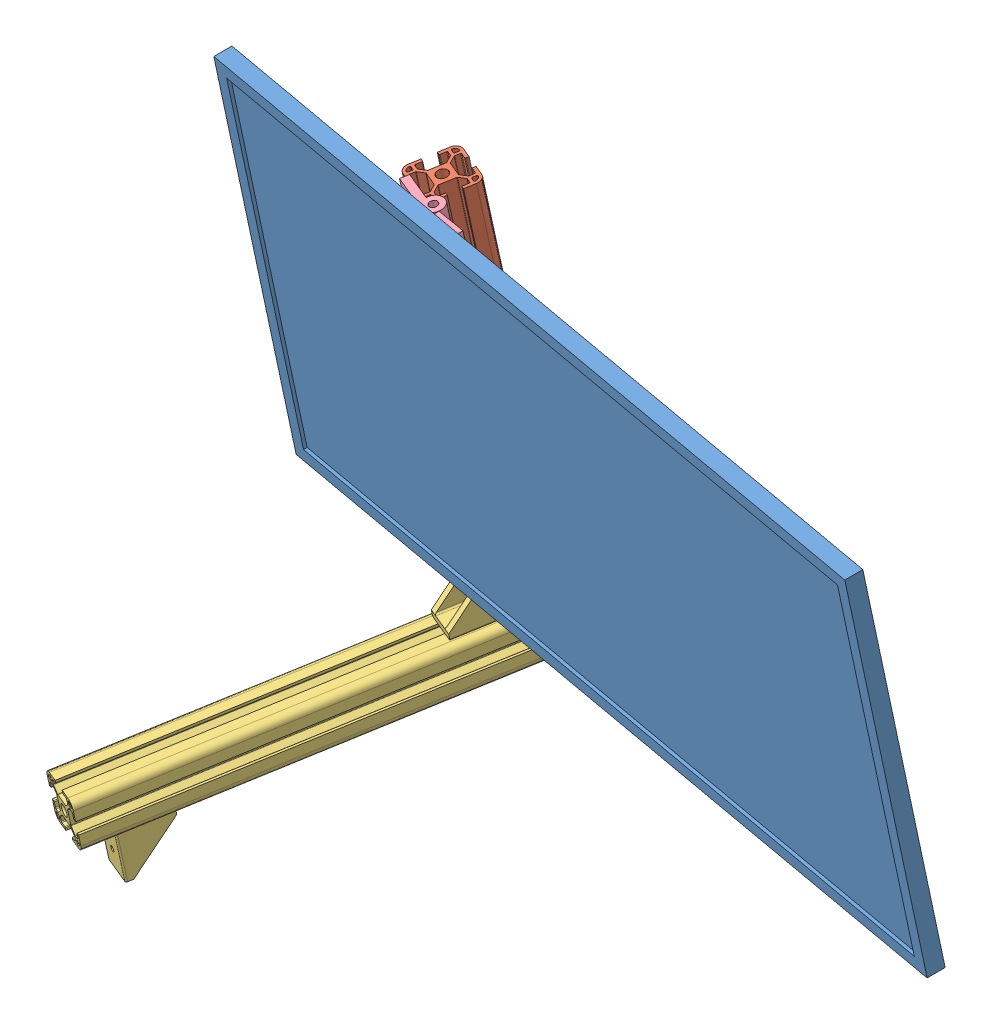
SolidWorks assembly 螢幕組, configuration 預設. Lengths in mm.
Overall size (544.01 439.81 254.23).
13 component instances, 4 part files, 25 mates.
Components (placement in the parent):
- 螢幕-1: 螢幕 [圓棒變滑塊] at (22.4284 66.6222 472.1885) x (0.983432 0.005828 0.181183) z (-0.177064 -0.183339 0.966972) size (500 240 30)
- 螢幕支架用鋁擠-2: 螢幕支架用鋁擠 [3030-250] at (88.7875 74.1628 449.5739) x (0.051386 -0.982878 -0.176946) z (0.982857 0.018358 0.183454) size (30 30 250)
- 鋁擠-2: 鋁擠 [溝槽] at (26.1822 70.509 451.6887) x (0.051386 -0.982878 -0.176946) z (0.982857 0.018358 0.183454) size (14.45 6.3 14)
- 鋁擠-3: 鋁擠 [3030-250] at (-252.8341 -209.0363 530.365) x (0.927532 -0.018707 0.373275) z (-0.370194 -0.183304 0.91069) size (30 30 250)
- 鋁擠-4: 鋁擠 [直角支架] at (-172.1622 -153.9662 332.6674) x (0.370194 0.183304 -0.91069) z (0.927532 -0.018707 0.373275) size (30 30 20)
- 鋁擠-5: 鋁擠 [溝槽] at (-178.3939 -158.2618 347.9368) x (-0.927532 0.018707 -0.373275) z (-0.370194 -0.183304 0.91069) size (14.45 6.3 14)
- 鉸鏈-1: 鉸鏈 [預設] at (-163.4821 123.0237 390.3048) x (0.982857 0.018358 0.183454) z (0.051386 -0.982878 -0.176946) size (50.7 17.96 50)
  - 鉸鏈-1: 鉸鏈 [左] at (0.4631 0.6018 25) size (31 12 50)
  - 鉸鏈-2: 鉸鏈 [右] at (0.4631 0.6018 25) x (0.979767 0.200143 0) z (0 0 1) size (31 12 50)
- 螢幕支架用鋁擠-1: 螢幕支架用鋁擠 [溝槽] at (-172.5916 -137.0373 334.5826) x (0.927532 -0.018707 0.373275) z (-0.051386 0.982878 0.176946) size (14.45 6.3 14)
- 螢幕支架用鋁擠-3: 螢幕支架用鋁擠 [3030-250] at (-166.6093 -151.2166 319.007) x (0.927532 -0.018707 0.373275) z (0.051386 -0.982878 -0.176946) size (30 30 250)
- 鋁擠-6: 鋁擠 [溝槽] at (-239.0663 -216.1339 495.7984) x (-0.927532 0.018707 -0.373275) z (0.370194 0.183304 -0.91069) size (14.45 6.3 14)
- 鋁擠-7: 鋁擠 [直角支架] at (-245.2979 -220.4296 511.0678) x (-0.370194 -0.183304 0.91069) z (0.927532 -0.018707 0.373275) size (30 30 20)
Mates (geometry in assembly coordinates):
- 重合/共線/共點1: coincident anti-aligned: plane of 螢幕支架用鋁擠-2 through (-159.4351 71.1214 416.9887) normal (0.177064 0.183339 -0.966972); plane of 鋁擠-2 through (33.0034 74.6174 452.8894) normal (-0.177064 -0.183339 0.966972)
- 同軸心1: concentric anti-aligned: cylinder of 螢幕-1 through (24.1991 68.4556 462.5188) axis (0.177064 0.183339 -0.966972) radius 1.65; cylinder of 鋁擠-2 through (26.1822 70.509 451.6887) axis (-0.177064 -0.183339 0.966972) radius 1.65
- 寬度1: width anti-aligned: plane of 鋁擠-2 through (33.3511 66.896 451.7993) normal (0.051386 -0.982878 -0.176946); plane of 鋁擠-2 through (32.9503 74.5624 453.1795) normal (-0.051386 0.982878 0.176946); plane of 螢幕支架用鋁擠-2 through (-159.3781 62.8917 417.5071) normal (-0.051386 0.982878 0.176946); plane of 螢幕支架用鋁擠-2 through (-159.7892 70.7547 418.9227) normal (0.051386 -0.982878 -0.176946)
- 重合/共線/共點2: coincident anti-aligned: plane of 螢幕-1 through (-2.3676 40.6232 442.0355) normal (0.177064 0.183339 -0.966972); plane of 螢幕支架用鋁擠-2 through (-160.1222 77.1434 420.073) normal (-0.177064 -0.183339 0.966972)
- 重合/共線/共點4: coincident anti-aligned: plane of 螢幕支架用鋁擠-2 through (-154.8103 82.6436 391.0638) normal (0.177064 0.183339 -0.966972); plane of 鉸鏈-1/鉸鏈-1 through (-190.0648 146.1799 396.6549) normal (-0.177064 -0.183339 0.966972)
- 同軸心2: concentric aligned: cylinder of 螢幕支架用鋁擠-2 through (-148.3032 81.3867 399.9354) axis (0.177064 0.183339 -0.966972) radius 2; cylinder of 鉸鏈-1/鉸鏈-1 through (-146.9476 82.7903 392.5324) axis (0.177064 0.183339 -0.966972) radius 2
- 同軸心3: concentric aligned: cylinder of 螢幕支架用鋁擠-2 through (-147.2755 61.7291 396.3965) axis (0.177064 0.183339 -0.966972) radius 2; cylinder of 鉸鏈-1/鉸鏈-1 through (-145.9199 63.1327 388.9935) axis (0.177064 0.183339 -0.966972) radius 2
- 同軸心5: concentric anti-aligned: cylinder of 鉸鏈-1/鉸鏈-2 through (-177.6375 82.7959 383.5888) axis (0.370194 0.183304 -0.91069) radius 2; cylinder of 螢幕支架用鋁擠-3 through (-172.9516 85.1161 372.0614) axis (-0.370194 -0.183304 0.91069) radius 2
- 同軸心6: concentric anti-aligned: cylinder of 鉸鏈-1/鉸鏈-2 through (-176.6097 63.1383 380.0498) axis (0.370194 0.183304 -0.91069) radius 2; cylinder of 螢幕支架用鋁擠-3 through (-171.9239 65.4586 368.5225) axis (-0.370194 -0.183304 0.91069) radius 2
- 重合/共線/共點6: coincident anti-aligned: plane of 鉸鏈-1/鉸鏈-2 through (-187.9895 148.0233 387.0182) normal (0.370194 0.183304 -0.91069); plane of 螢幕支架用鋁擠-3 through (-194.7479 91.9498 372.9845) normal (-0.370194 -0.183304 0.91069)
- 重合/共線/共點7: coincident anti-aligned: plane of 螢幕支架用鋁擠-1 through (-176.2725 -129.9376 333.6369) normal (-0.370194 -0.183304 0.91069); plane of 螢幕支架用鋁擠-3 through (-187.9786 92.1958 373.5896) normal (0.370194 0.183304 -0.91069)
- 寬度2: width aligned: plane of 螢幕支架用鋁擠-1 through (-176.3835 -129.9926 333.9102) normal (-0.927532 0.018707 -0.373275); plane of 螢幕支架用鋁擠-1 through (-169.1488 -130.1385 336.8217) normal (0.927532 -0.018707 0.373275); plane of 螢幕支架用鋁擠-3 through (-181.2987 91.6795 378.3971) normal (-0.927532 0.018707 -0.373275); plane of 螢幕支架用鋁擠-3 through (-188.719 91.8292 375.4109) normal (0.927532 -0.018707 0.373275)
- 同軸心7: concentric aligned: cylinder of 鋁擠-4 through (-174.5166 -137.9905 339.3182) axis (-0.370194 -0.183304 0.91069) radius 1.65; cylinder of 螢幕支架用鋁擠-1 through (-172.5916 -137.0373 334.5826) axis (-0.370194 -0.183304 0.91069) radius 1.65
- 重合/共線/共點8: coincident anti-aligned: plane of 鋁擠-4 through (-162.8869 -154.1533 336.4001) normal (0.370194 0.183304 -0.91069); plane of 螢幕支架用鋁擠-3 through (-194.7479 91.9498 372.9845) normal (-0.370194 -0.183304 0.91069)
- 重合/共線/共點9: coincident anti-aligned: plane of 鋁擠-3 through (-164.6634 -150.3578 303.4988) normal (0.051386 -0.982878 -0.176946); plane of 鋁擠-5 through (-177.3267 -160.4042 355.6258) normal (-0.051386 0.982878 0.176946)
- 寬度3: width anti-aligned: plane of 鋁擠-5 through (-184.5769 -159.9634 352.7674) normal (-0.927532 0.018707 -0.373275); plane of 鋁擠-5 through (-177.3421 -160.1094 355.6789) normal (0.927532 -0.018707 0.373275); plane of 鋁擠-3 through (-164.7662 -148.3921 303.8527) normal (0.927532 -0.018707 0.373275); plane of 鋁擠-3 through (-157.3459 -148.5417 306.8389) normal (-0.927532 0.018707 -0.373275)
- 同軸心8: concentric aligned: cylinder of 鋁擠-4 through (-178.6611 -153.1509 348.8569) axis (-0.051386 0.982878 0.176946) radius 1.65; cylinder of 鋁擠-5 through (-178.3939 -158.2618 347.9368) axis (-0.051386 0.982878 0.176946) radius 1.65
- 重合/共線/共點10: coincident anti-aligned: plane of 鋁擠-3 through (-170.7955 -148.2707 301.4273) normal (-0.051386 0.982878 0.176946); plane of 鋁擠-4 through (-162.8869 -154.1533 336.4001) normal (0.051386 -0.982878 -0.176946)
- 重合/共線/共點11: coincident anti-aligned: plane of 鋁擠-3 through (-170.7955 -148.2707 301.4273) normal (-0.051386 0.982878 0.176946); plane of 螢幕支架用鋁擠-3 through (-180.2354 -152.9449 324.6499) normal (0.051386 -0.982878 -0.176946)
- 重合/共線/共點12: coincident aligned: plane of 鋁擠-3 through (-170.5643 -152.6936 300.6311) normal (0.370194 0.183304 -0.91069); plane of 螢幕支架用鋁擠-3 through (-183.642 97.4489 345.6638) normal (0.370194 0.183304 -0.91069)
- 重合/共線/共點13: coincident anti-aligned: plane of 鋁擠-3 through (-155.9071 -176.0623 301.8844) normal (-0.051386 0.982878 0.176946); plane of 鋁擠-6 through (-232.8987 -214.1375 491.0209) normal (0.051386 -0.982878 -0.176946)
- 寬度4: width aligned: plane of 鋁擠-6 through (-240.118 -214.2864 488.0563) normal (-0.927532 0.018707 -0.373275); plane of 鋁擠-6 through (-232.8833 -214.4323 490.9678) normal (0.927532 -0.018707 0.373275); plane of 鋁擠-3 through (-155.8043 -178.0281 301.5305) normal (-0.927532 0.018707 -0.373275); plane of 鋁擠-3 through (-163.2246 -177.8784 298.5443) normal (0.927532 -0.018707 0.373275)
- 同軸心9: concentric aligned: cylinder of 鋁擠-6 through (-239.0663 -216.1339 495.7984) axis (0.051386 -0.982878 -0.176946) radius 1.65; cylinder of 鋁擠-7 through (-238.7991 -221.2449 494.8783) axis (0.051386 -0.982878 -0.176946) radius 1.65
- 重合/共線/共點14: coincident anti-aligned: plane of 鋁擠-3 through (-169.2539 -177.757 296.1189) normal (0.051386 -0.982878 -0.176946); plane of 鋁擠-7 through (-236.0226 -220.6166 514.8006) normal (-0.051386 0.982878 0.176946)
- 平行(R)1: parallel aligned: plane of 鋁擠-3 through (-263.1127 -198.5196 528.3035) normal (-0.370194 -0.183304 0.91069); plane of 鋁擠-7 through (-236.0226 -220.6166 514.8006) normal (-0.370194 -0.183304 0.91069)
